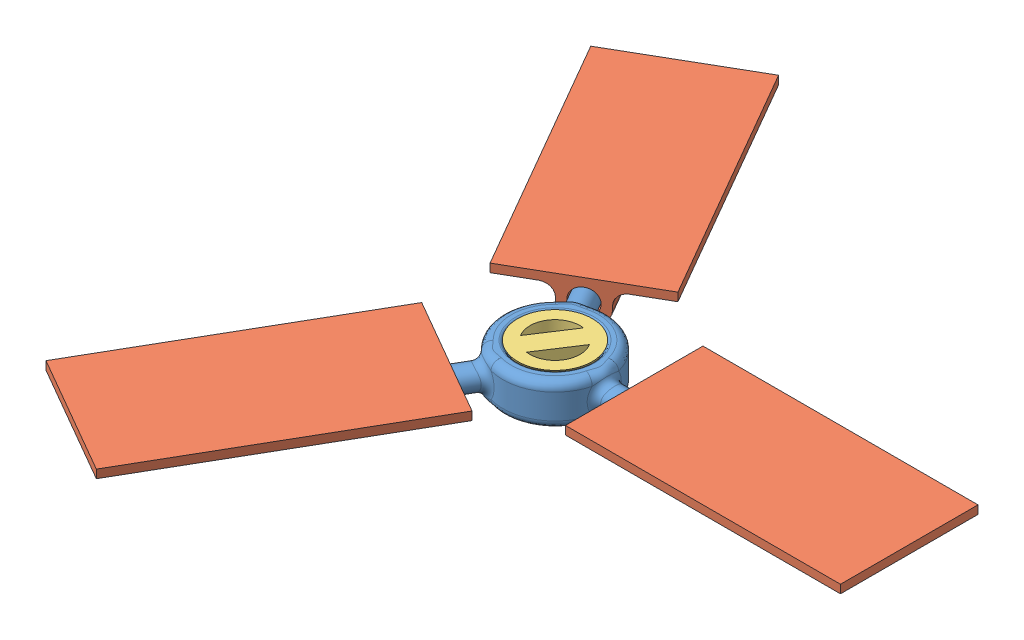
SolidWorks assembly toyModel3, configuration Default. Lengths in mm.
Overall size (141.79 10.18 163.72).
5 component instances, 3 part files, 4 mates.
Components (placement in the parent):
- toyModel3-1: toyModel3 [Default] at (6.4822 21.5523 40.4616) size (50.33 10.18 51.38)
- toyModel3_1-1: toyModel3_1 [Default] at (25.4798 26.5523 40.4616) size (66 9 33)
- toyModel3_1-2: toyModel3_1 [Default] at (-3.0166 26.5523 56.914) x (-0.5 0 0.866025) z (-0.866025 0 -0.5) size (66 9 33)
- toyModel3_1-3: toyModel3_1 [Default] at (-3.0166 26.5523 24.0092) x (-0.5 0 -0.866025) z (0.866025 0 -0.5) size (66 9 33)
- toyModel4-1: toyModel4 [Default] at (6.4822 31.5523 40.4616) x (-0.837169 0 -0.546944) z (-0.546944 0 0.837169) size (17.86 10 17.86)
Mates (geometry in assembly coordinates):
- Concentric1: concentric anti-aligned: cylinder of toyModel3-1 through (15.9822 26.5523 40.4616) axis (1 0 0) radius 2.75; cylinder of toyModel3_1-1 through (28.0798 26.5523 40.4616) axis (-1 0 0) radius 3.025
- Parallel1: parallel aligned: plane of toyModel3-1 through (6.4822 31.5523 40.4616) normal (0 1 0); plane of toyModel3_1-1 through (25.4798 31.5523 40.4616) normal (0 1 0)
- Coincident1: coincident aligned: plane of toyModel3-1 through (6.4822 31.5523 40.4616) normal (0 1 0); plane of toyModel4-1 through (6.4822 31.5523 40.4616) normal (0 1 0)
- Concentric3: concentric anti-aligned: circle of toyModel3-1; circle of toyModel4-1
